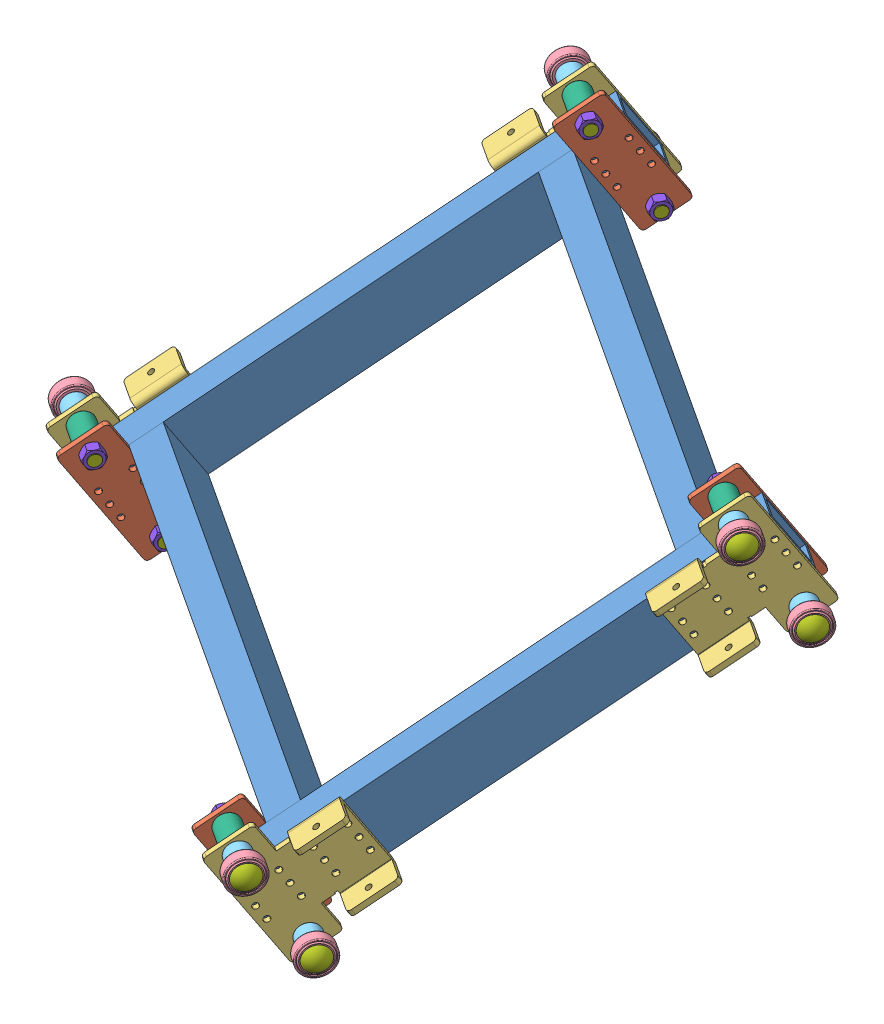
SolidWorks assembly carrige assembly, configuration Default. Lengths in mm.
Overall size (656.01 311.13 618.97).
56 component instances, 8 part files, 21 mates.
Components (placement in the parent):
- 15 7 8 height-1: 15 7 8 height [Default] at (347.2127 190.7533 277.6779) x (-0.299148 0.837169 0.457885) z (-0.457885 -0.546944 0.700852) size (50.8 403.23 25.4)
- 15 7 8 height-2: 15 7 8 height [Default] at (397.5525 225.4843 247.0662) x (-0.299148 0.837169 0.457885) z (0.837169 0 0.546944) size (50.8 403.23 25.4)
- 15 7 8 height-3: 15 7 8 height [Default] at (38.7209 225.4843 12.6323) x (-0.299148 0.837169 0.457885) z (0.837169 0 0.546944) size (50.8 403.23 25.4)
- 15 7 8 height-4: 15 7 8 height [Default] at (-116.834 39.6737 250.7293) x (-0.299148 0.837169 0.457885) z (0.457885 0.546944 -0.700852) size (50.8 403.23 25.4)
- Roller-2: Roller [Défaut] at (218.0312 36.6261 530.5498) x (-0.299148 0.837169 0.457885) z (0.457885 0.546944 -0.700852) size (108.2 74.88 88.9)
  - am3793a-1: am3793a [Défaut] at (0 -30.16 0) size (101.6 4.76 38.1)
  - am3794a-1: am3794a [Défaut] at origin size (101.6 25 88.9)
  - am-0209b-1: am-0209b [Défaut] at (-39.8145 20.6375 0) x (1 0 0) z (0 1 0) size (28.57 28.57 9.53)
  - am1451-1: am1451 [Défaut] at (-39.8145 7.9375 0) x (0 0 1) z (-1 0 0) size (19.05 15.88 19.05)
  - am1451-2: am1451 [Défaut] at (39.8145 7.9375 0) x (-1 0 0) z (0 0 -1) size (19.05 15.88 19.05)
  - am-0209b-3: am-0209b [Défaut] at (39.8145 20.6375 0) x (1 0 0) z (0 1 0) size (28.57 28.57 9.53)
  - am1450-1: am1450 [Défaut] at (-39.8145 -17.46 0) size (19.05 25.4 19.05)
  - am1450-2: am1450 [Défaut] at (39.8145 -17.46 0) size (19.05 25.4 19.05)
  - round head bolt_ai-2: round head bolt_ai [RHBOLT 0.375-16x2.75x1-C] at (-39.8145 30.4292 0) x (0 -1 0) z (-1 0 0) size (74.88 20.65 20.65)
  - round head bolt_ai-3: round head bolt_ai [RHBOLT 0.375-16x2.75x1-C] at (39.8145 30.4292 0) x (0 -1 0) z (-1 0 0) size (74.88 20.65 20.65)
  - hex nut_ai-1: hex nut_ai [HNUT 0.3750-16-D-N] at (39.8145 -43.4798 0) x (0 0 1) z (0 -1 0) size (14.27 16.48 8.56)
  - hex nut_ai-2: hex nut_ai [HNUT 0.3750-16-D-N] at (-39.8145 -43.4798 0) x (0 0 1) z (0 -1 0) size (14.27 16.48 8.56)
- Roller-3: Roller [Défaut] at (-170.0343 36.6261 277.0166) x (0.299148 -0.837169 -0.457885) z (0.457885 0.546944 -0.700852) size (108.2 74.88 88.9)
  - am3793a-1: am3793a [Défaut] at (0 -30.16 0) size (101.6 4.76 38.1)
  - am3794a-1: am3794a [Défaut] at origin size (101.6 25 88.9)
  - am-0209b-1: am-0209b [Défaut] at (-39.8145 20.6375 0) x (1 0 0) z (0 1 0) size (28.57 28.57 9.53)
  - am1451-1: am1451 [Défaut] at (-39.8145 7.9375 0) x (0 0 1) z (-1 0 0) size (19.05 15.88 19.05)
  - am1451-2: am1451 [Défaut] at (39.8145 7.9375 0) x (-1 0 0) z (0 0 -1) size (19.05 15.88 19.05)
  - am-0209b-3: am-0209b [Défaut] at (39.8145 20.6375 0) x (1 0 0) z (0 1 0) size (28.57 28.57 9.53)
  - am1450-1: am1450 [Défaut] at (-39.8145 -17.46 0) size (19.05 25.4 19.05)
  - am1450-2: am1450 [Défaut] at (39.8145 -17.46 0) size (19.05 25.4 19.05)
  - round head bolt_ai-2: round head bolt_ai [RHBOLT 0.375-16x2.75x1-C] at (-39.8145 30.4292 0) x (0 -1 0) z (-1 0 0) size (74.88 20.65 20.65)
  - round head bolt_ai-3: round head bolt_ai [RHBOLT 0.375-16x2.75x1-C] at (39.8145 30.4292 0) x (0 -1 0) z (-1 0 0) size (74.88 20.65 20.65)
  - hex nut_ai-1: hex nut_ai [HNUT 0.3750-16-D-N] at (39.8145 -43.4798 0) x (0 0 1) z (0 -1 0) size (14.27 16.48 8.56)
  - hex nut_ai-2: hex nut_ai [HNUT 0.3750-16-D-N] at (-39.8145 -43.4798 0) x (0 0 1) z (0 -1 0) size (14.27 16.48 8.56)
- Roller-4: Roller [Défaut] at (385.2164 236.3291 274.6512) x (0.299148 -0.837169 -0.457885) z (-0.457885 -0.546944 0.700852) size (108.2 74.88 88.9)
  - am3793a-1: am3793a [Défaut] at (0 -30.16 0) size (101.6 4.76 38.1)
  - am3794a-1: am3794a [Défaut] at origin size (101.6 25 88.9)
  - am-0209b-1: am-0209b [Défaut] at (-39.8145 20.6375 0) x (1 0 0) z (0 1 0) size (28.57 28.57 9.53)
  - am1451-1: am1451 [Défaut] at (-39.8145 7.9375 0) x (0 0 1) z (-1 0 0) size (19.05 15.88 19.05)
  - am1451-2: am1451 [Défaut] at (39.8145 7.9375 0) x (-1 0 0) z (0 0 -1) size (19.05 15.88 19.05)
  - am-0209b-3: am-0209b [Défaut] at (39.8145 20.6375 0) x (1 0 0) z (0 1 0) size (28.57 28.57 9.53)
  - am1450-1: am1450 [Défaut] at (-39.8145 -17.46 0) size (19.05 25.4 19.05)
  - am1450-2: am1450 [Défaut] at (39.8145 -17.46 0) size (19.05 25.4 19.05)
  - round head bolt_ai-2: round head bolt_ai [RHBOLT 0.375-16x2.75x1-C] at (-39.8145 30.4292 0) x (0 -1 0) z (-1 0 0) size (74.88 20.65 20.65)
  - round head bolt_ai-3: round head bolt_ai [RHBOLT 0.375-16x2.75x1-C] at (39.8145 30.4292 0) x (0 -1 0) z (-1 0 0) size (74.88 20.65 20.65)
  - hex nut_ai-1: hex nut_ai [HNUT 0.3750-16-D-N] at (39.8145 -43.4798 0) x (0 0 1) z (0 -1 0) size (14.27 16.48 8.56)
  - hex nut_ai-2: hex nut_ai [HNUT 0.3750-16-D-N] at (-39.8145 -43.4798 0) x (0 0 1) z (0 -1 0) size (14.27 16.48 8.56)
- Roller-5: Roller [Défaut] at (-2.8492 236.3291 21.1179) x (-0.299148 0.837169 0.457885) z (-0.457885 -0.546944 0.700852) size (108.2 74.88 88.9)
  - am3793a-1: am3793a [Défaut] at (0 -30.16 0) size (101.6 4.76 38.1)
  - am3794a-1: am3794a [Défaut] at origin size (101.6 25 88.9)
  - am-0209b-1: am-0209b [Défaut] at (-39.8145 20.6375 0) x (1 0 0) z (0 1 0) size (28.57 28.57 9.53)
  - am1451-1: am1451 [Défaut] at (-39.8145 7.9375 0) x (0 0 1) z (-1 0 0) size (19.05 15.88 19.05)
  - am1451-2: am1451 [Défaut] at (39.8145 7.9375 0) x (-1 0 0) z (0 0 -1) size (19.05 15.88 19.05)
  - am-0209b-3: am-0209b [Défaut] at (39.8145 20.6375 0) x (1 0 0) z (0 1 0) size (28.57 28.57 9.53)
  - am1450-1: am1450 [Défaut] at (-39.8145 -17.46 0) size (19.05 25.4 19.05)
  - am1450-2: am1450 [Défaut] at (39.8145 -17.46 0) size (19.05 25.4 19.05)
  - round head bolt_ai-2: round head bolt_ai [RHBOLT 0.375-16x2.75x1-C] at (-39.8145 30.4292 0) x (0 -1 0) z (-1 0 0) size (74.88 20.65 20.65)
  - round head bolt_ai-3: round head bolt_ai [RHBOLT 0.375-16x2.75x1-C] at (39.8145 30.4292 0) x (0 -1 0) z (-1 0 0) size (74.88 20.65 20.65)
  - hex nut_ai-1: hex nut_ai [HNUT 0.3750-16-D-N] at (39.8145 -43.4798 0) x (0 0 1) z (0 -1 0) size (14.27 16.48 8.56)
  - hex nut_ai-2: hex nut_ai [HNUT 0.3750-16-D-N] at (-39.8145 -43.4798 0) x (0 0 1) z (0 -1 0) size (14.27 16.48 8.56)
Mates (geometry in assembly coordinates):
- Coincident1: coincident anti-aligned: plane of 15 7 8 height-2 through (191.6578 4.9427 515.7749) normal (-0.837169 0 -0.546944); plane of 15 7 8 height-4 through (220.7335 39.6737 471.2708) normal (0.837169 0 0.546944)
- Coincident3: coincident aligned: plane of 15 7 8 height-2 through (212.9219 4.9427 529.6673) normal (0.299148 -0.837169 -0.457885); plane of 15 7 8 height-4 through (220.7335 39.6737 471.2708) normal (0.299148 -0.837169 -0.457885)
- Coincident4: coincident anti-aligned: plane of 15 7 8 height-3 through (-145.9097 4.9427 295.2334) normal (0.837169 0 0.546944); plane of 15 7 8 height-4 through (-116.834 39.6737 250.7293) normal (-0.837169 0 -0.546944)
- Coincident5: coincident aligned: plane of 15 7 8 height-3 through (-145.9097 4.9427 295.2334) normal (0.299148 -0.837169 -0.457885); plane of 15 7 8 height-4 through (220.7335 39.6737 471.2708) normal (0.299148 -0.837169 -0.457885)
- Coincident7: coincident anti-aligned: plane of 15 7 8 height-1 through (9.6452 190.7533 57.1364) normal (-0.837169 0 -0.546944); plane of 15 7 8 height-3 through (-145.9097 4.9427 295.2334) normal (0.837169 0 0.546944)
- Coincident8: coincident aligned: plane of 15 7 8 height-1 through (9.6452 190.7533 57.1364) normal (0.299148 -0.837169 -0.457885); plane of 15 7 8 height-3 through (-145.9097 4.9427 295.2334) normal (0.299148 -0.837169 -0.457885)
- Distance6: distance = 38.1 mm aligned: plane of 15 7 8 height-3 through (-145.9097 4.9427 295.2334) normal (-0.457885 -0.546944 0.700852); plane of 15 7 8 height-4 through (209.1032 25.7813 489.0724) normal (-0.457885 -0.546944 0.700852)
- Distance7: distance = 38.1 mm aligned: plane of 15 7 8 height-4 through (209.1032 25.7813 489.0724) normal (-0.457885 -0.546944 0.700852); plane of 15 7 8 height-2 through (212.9219 4.9427 529.6673) normal (-0.457885 -0.546944 0.700852)
- Distance8: distance = 38.1 mm aligned: plane of 15 7 8 height-1 through (21.2755 204.6457 39.3347) normal (0.457885 0.546944 -0.700852); plane of 15 7 8 height-3 through (38.7209 225.4843 12.6323) normal (0.457885 0.546944 -0.700852)
- Coincident12: coincident anti-aligned: plane of 15 7 8 height-2 through (191.6578 4.9427 515.7749) normal (-0.837169 0 -0.546944); plane of Roller-2/am3793a-1 through (192.7822 36.6261 514.054) normal (0.837169 0 0.546944)
- Coincident13: coincident aligned: plane of 15 7 8 height-2 through (212.9219 4.9427 529.6673) normal (-0.457885 -0.546944 0.700852); plane of Roller-2/am3793a-1 through (164.8778 68.735 548.0623) normal (-0.457885 -0.546944 0.700852)
- Coincident19: coincident aligned: plane of 15 7 8 height-2 through (212.9219 4.9427 529.6673) normal (0.299148 -0.837169 -0.457885); plane of Roller-2/am3794a-1 through (230.3673 25.7813 502.9648) normal (0.299148 -0.837169 -0.457885)
- Coincident20: coincident anti-aligned: plane of 15 7 8 height-3 through (-167.1738 4.9427 281.341) normal (-0.837169 0 -0.546944); plane of Roller-3/am3794a-1 through (-166.0494 36.6261 279.62) normal (0.837169 0 0.546944)
- Coincident21: coincident aligned: plane of 15 7 8 height-3 through (-145.9097 4.9427 295.2334) normal (-0.457885 -0.546944 0.700852); plane of Roller-3/am3794a-1 through (-159.5754 -16.3213 269.7107) normal (-0.457885 -0.546944 0.700852)
- Coincident22: coincident aligned: plane of 15 7 8 height-3 through (-161.1064 47.4709 318.4939) normal (-0.299148 0.837169 0.457885); plane of Roller-3/am3794a-1 through (-164.9251 68.3095 277.8991) normal (-0.299148 0.837169 0.457885)
- Coincident23: coincident anti-aligned: plane of 15 7 8 height-2 through (212.9219 4.9427 529.6673) normal (0.837169 0 0.546944); plane of Roller-4/am3794a-1 through (381.2314 236.3291 272.0477) normal (-0.837169 0 -0.546944)
- Coincident24: coincident aligned: plane of 15 7 8 height-2 through (397.5525 225.4843 247.0662) normal (0.457885 0.546944 -0.700852); plane of Roller-4/am3794a-1 through (405.1509 204.2202 235.4359) normal (0.457885 0.546944 -0.700852)
- Coincident25: coincident aligned: plane of 15 7 8 height-2 through (212.9219 4.9427 529.6673) normal (0.299148 -0.837169 -0.457885); plane of Roller-4/am3794a-1 through (380.1071 204.6457 273.7687) normal (0.299148 -0.837169 -0.457885)
- Coincident26: coincident anti-aligned: plane of 15 7 8 height-3 through (-167.1738 4.9427 281.341) normal (-0.837169 0 -0.546944); plane of Roller-5/am3794a-1 through (1.1357 236.3291 23.7214) normal (0.837169 0 0.546944)
- Coincident27: coincident aligned: plane of 15 7 8 height-3 through (38.7209 225.4843 12.6323) normal (0.457885 0.546944 -0.700852); plane of Roller-5/am3794a-1 through (-5.3383 289.2766 33.6307) normal (0.457885 0.546944 -0.700852)
- Coincident28: coincident aligned: plane of 15 7 8 height-3 through (-145.9097 4.9427 295.2334) normal (0.299148 -0.837169 -0.457885); plane of Roller-5/am3794a-1 through (0.0114 204.6457 25.4424) normal (0.299148 -0.837169 -0.457885)
